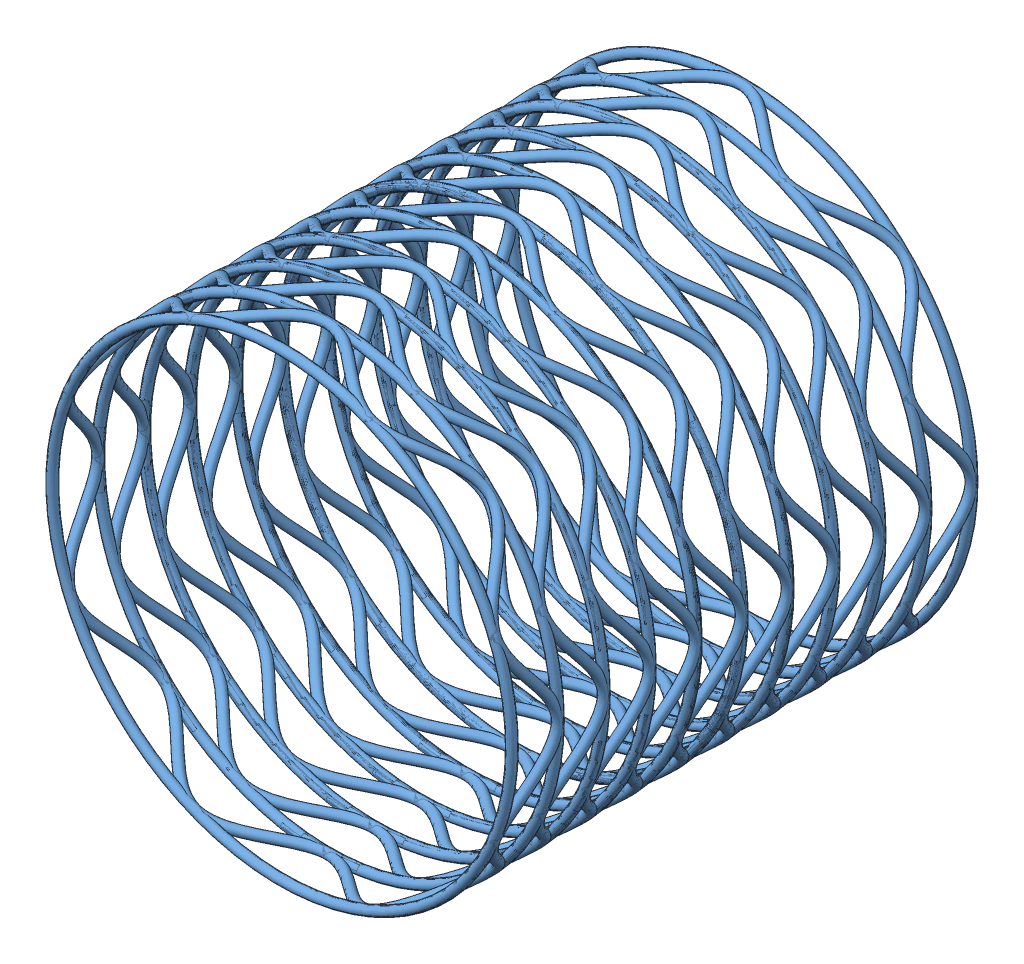
SolidWorks assembly stent-mpang, configuration Default. Lengths in mm.
Overall size (102.76 102.76 102).
10 component instances, 1 part files, 0 mates.
Components (placement in the parent):
- stench-mpang-1: stench-mpang [Default] at (50.5604 49.3676 75.3256) size (102.76 102.76 12)
- stench-mpang-2: stench-mpang [Default] at (50.5604 49.3676 85.3256) size (102.76 102.76 12)
- stench-mpang-3: stench-mpang [Default] at (50.5604 49.3676 95.3256) size (102.76 102.76 12)
- stench-mpang-4: stench-mpang [Default] at (50.5604 49.3676 105.3256) size (102.76 102.76 12)
- stench-mpang-5: stench-mpang [Default] at (50.5604 49.3676 115.3256) size (102.76 102.76 12)
- stench-mpang-6: stench-mpang [Default] at (50.5604 49.3676 125.3256) size (102.76 102.76 12)
- stench-mpang-7: stench-mpang [Default] at (50.5604 49.3676 135.3256) size (102.76 102.76 12)
- stench-mpang-8: stench-mpang [Default] at (50.5604 49.3676 145.3256) size (102.76 102.76 12)
- stench-mpang-9: stench-mpang [Default] at (50.5604 49.3676 155.3256) size (102.76 102.76 12)
- stench-mpang-10: stench-mpang [Default] at (50.5604 49.3676 165.3256) size (102.76 102.76 12)
